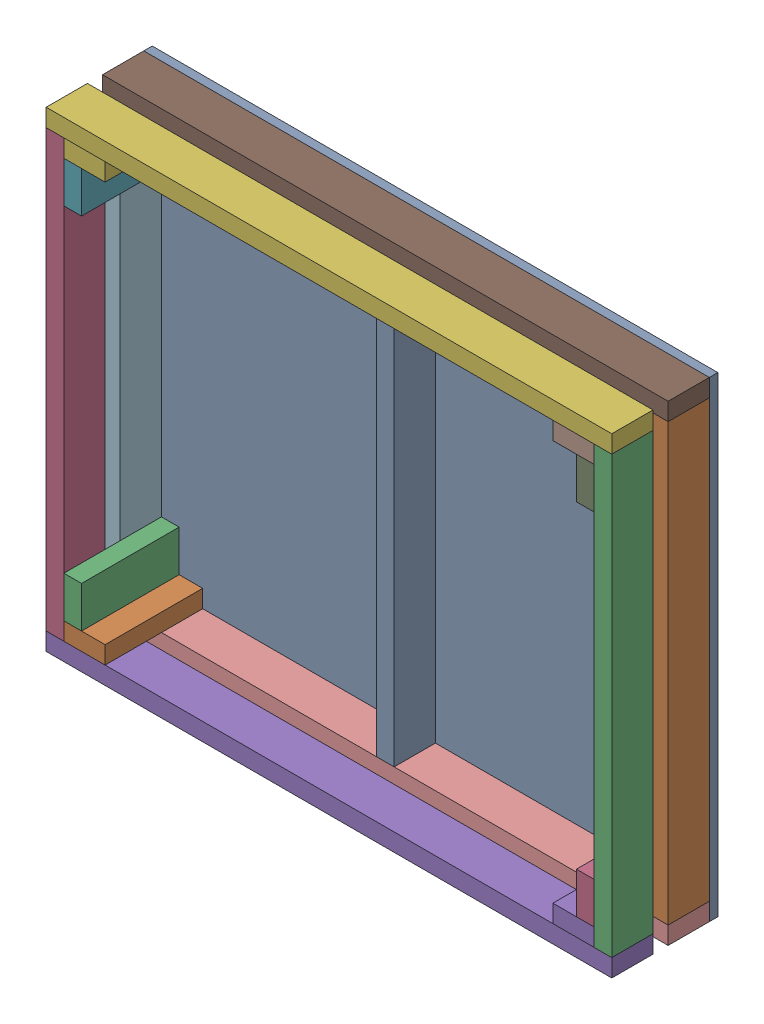
SolidWorks assembly TE-19103, configuration Default. Lengths in mm.
Overall size (1219.2 1016 228.6).
18 component instances, 4 part files, 61 mates.
Components (placement in the parent):
- TE-19103-01-1: TE-19103-01 [Default] at (153.7904 631.9704 926.4569) size (1219.2 1016 18.26)
- TE-19103-02-1: TE-19103-02 [Default] at (-77.2876 195.0062 1155.0569) x (-1 0 0) z (0 0 -1) size (88.9 38.1 210.34)
- TE-19103-02-2: TE-19103-02 [Default] at (-115.6981 316.4092 1155.0569) x (0 -1 0) z (0 0 -1) size (88.9 38.1 210.34)
- TE-19103-02-3: TE-19103-02 [Default] at (989.2019 316.4092 1155.0569) x (0 -1 0) z (0 0 -1) size (88.9 38.1 210.34)
- TE-19103-02-4: TE-19103-02 [Default] at (976.8124 195.0062 1155.0569) x (-1 0 0) z (0 0 -1) size (88.9 38.1 210.34)
- TE-19103-02-5: TE-19103-02 [Default] at (-148.2012 1141.5986 1155.0569) x (1 0 0) z (0 0 -1) size (88.9 38.1 210.34)
- TE-19103-02-6: TE-19103-02 [Default] at (-115.6981 1091.1092 1155.0569) x (0 -1 0) z (0 0 -1) size (88.9 38.1 210.34)
- TE-19103-02-7: TE-19103-02 [Default] at (976.8124 1096.7062 1155.0569) x (-1 0 0) z (0 0 -1) size (88.9 38.1 210.34)
- TE-19103-02-8: TE-19103-02 [Default] at (989.2019 1091.1092 1155.0569) x (0 -1 0) z (0 0 -1) size (88.9 38.1 210.34)
- TE-19103-03-1: TE-19103-03 [Default] at (-195.2944 160.3024 995.9796) x (0 -1 0) z (1 0 0) size (38.1 88.9 1219.2)
- TE-19103-03-2: TE-19103-03 [Default] at (1023.9056 1176.3024 995.9796) x (0 1 0) z (-1 0 0) size (38.1 88.9 1219.2)
- TE-19103-04-1: TE-19103-04 [Default] at (-157.1944 198.4024 1009.1746) x (1 0 0) z (0 1 0) size (38.1 88.9 939.8)
- TE-19103-04-2: TE-19103-04 [Default] at (433.3556 198.4024 1009.1746) x (1 0 0) z (0 1 0) size (38.1 88.9 939.8)
- TE-19103-04-3: TE-19103-04 [Default] at (1023.9056 1138.2024 969.1516) x (1 0 0) z (0 -1 0) size (38.1 88.9 939.8)
- TE-19103-04-4: TE-19103-04 [Default] at (985.8056 1138.2024 1130.6184) x (-1 0 0) z (0 -1 0) size (38.1 88.9 939.8)
- TE-19103-04-5: TE-19103-04 [Default] at (-157.1944 198.4024 1130.6184) x (1 0 0) z (0 1 0) size (38.1 88.9 939.8)
- TE-19103-03-3: TE-19103-03 [Default] at (1023.9056 160.3024 1103.7904) x (0 -1 0) z (-1 0 0) size (38.1 88.9 1219.2)
- TE-19103-03-4: TE-19103-03 [Default] at (1023.9056 1176.3024 1117.4233) x (0 1 0) z (-1 0 0) size (38.1 88.9 1219.2)
Mates (geometry in assembly coordinates):
- Coincident1: coincident: plane of TE-19103-01-1 through (153.7904 631.9704 944.7131) normal (0 0 1); plane of TE-19103-03-2 through (-195.2944 1138.2024 944.7131) normal (0 0 -1)
- Coincident2: coincident: plane of TE-19103-01-1 through (-195.2944 1176.3024 944.7131) normal (0 1 0); plane of TE-19103-03-2 through (-195.2944 1176.3024 944.7131) normal (0 1 0)
- Coincident3: coincident: plane of TE-19103-01-1 through (1023.9056 1176.3024 944.7131) normal (1 0 0); plane of TE-19103-03-2 through (1023.9056 1176.3024 995.9796) normal (1 0 0)
- Coincident4: coincident: plane of TE-19103-01-1 through (153.7904 631.9704 944.7131) normal (0 0 1); plane of TE-19103-03-1 through (1023.9056 198.4024 944.7131) normal (0 0 -1)
- Coincident6: coincident: plane of assembly; plane of assembly; plane of TE-19103-03-1 through (1023.9056 160.3024 995.9796) normal (1 0 0); plane of TE-19103-03-2 through (1023.9056 1176.3024 995.9796) normal (1 0 0)
- Coincident7: coincident: plane of TE-19103-01-1 through (-195.2944 160.3024 944.7131) normal (0 -1 0); plane of TE-19103-03-1 through (1023.9056 160.3024 944.7131) normal (0 -1 0)
- Coincident8: coincident: plane of TE-19103-01-1 through (153.7904 631.9704 944.7131) normal (0 0 1); plane of TE-19103-04-3 through (985.8056 198.4024 944.7131) normal (0 0 -1)
- Coincident9: coincident: plane of assembly; plane of assembly; plane of TE-19103-03-1 through (1023.9056 198.4024 944.7131) normal (0 1 0); plane of TE-19103-04-3 through (1023.9056 198.4024 969.1516) normal (0 -1 0)
- Coincident10: coincident: plane of assembly; plane of assembly; plane of TE-19103-03-1 through (1023.9056 160.3024 995.9796) normal (1 0 0); plane of TE-19103-04-3 through (1023.9056 198.4024 1033.6131) normal (1 0 0)
- Coincident11: coincident: plane of assembly; plane of assembly; plane of TE-19103-03-2 through (-195.2944 1138.2024 944.7131) normal (0 -1 0); plane of TE-19103-04-1 through (-157.1944 1138.2024 1009.1746) normal (0 1 0)
- Coincident12: coincident: plane of TE-19103-01-1 through (153.7904 631.9704 944.7131) normal (0 0 1); plane of TE-19103-04-1 through (-195.2944 1138.2024 944.7131) normal (0 0 -1)
- Coincident13: coincident: plane of assembly; plane of assembly; plane of TE-19103-03-2 through (-195.2944 1176.3024 995.9796) normal (-1 0 0); plane of TE-19103-04-1 through (-195.2944 1138.2024 944.7131) normal (-1 0 0)
- Coincident14: coincident: plane of TE-19103-02-5 through (-157.1944 1100.1024 944.7131) normal (0 -1 0); unknown of ?
- Coincident15: coincident: plane of assembly; plane of assembly; plane of TE-19103-02-5 through (-148.2012 1141.5986 944.7131) normal (0 0 -1); plane of TE-19103-02-6 through (-115.6981 1091.1092 944.7131) normal (0 0 -1)
- Coincident16: coincident: plane of TE-19103-02-5 through (-157.1944 1100.1024 944.7131) normal (-1 0 0); unknown of ?
- Coincident17: coincident: plane of TE-19103-01-1 through (153.7904 631.9704 944.7131) normal (0 0 1); plane of TE-19103-02-6 through (-115.6981 1091.1092 944.7131) normal (0 0 -1)
- Coincident18: coincident: plane of assembly; plane of assembly; plane of TE-19103-02-5 through (-157.1944 1138.2024 944.7131) normal (0 1 0); plane of TE-19103-03-2 through (-195.2944 1138.2024 944.7131) normal (0 -1 0)
- Coincident19: coincident: unknown of ?; plane of TE-19103-04-1 through (-157.1944 1138.2024 944.7131) normal (1 0 0)
- Symmetric1: symmetric: plane of assembly; plane of assembly; plane of TE-19103-04-2 through (433.3556 1138.2024 944.7131) normal (1 0 0); plane of TE-19103-04-2 through (395.2556 1138.2024 944.7131) normal (-1 0 0); plane of assembly
- Coincident20: coincident: plane of TE-19103-01-1 through (153.7904 631.9704 944.7131) normal (0 0 1); plane of TE-19103-04-2 through (395.2556 1138.2024 944.7131) normal (0 0 -1)
- Coincident21: coincident: plane of assembly; plane of assembly; plane of TE-19103-03-1 through (1023.9056 198.4024 944.7131) normal (0 1 0); plane of TE-19103-04-2 through (433.3556 198.4024 1009.1746) normal (0 -1 0)
- Coincident22: coincident: plane of TE-19103-02-7 through (985.8056 1100.1024 944.7131) normal (0 -1 0); plane of ? through (985.8056 1100.1024 944.7131) normal (0 1 0)
- Coincident23: coincident: plane of TE-19103-02-7 through (896.9056 1138.2024 944.7131) normal (-1 0 0); plane of ? through (896.9056 1100.1024 944.7131) normal (-1 0 0)
- Coincident24: coincident: plane of assembly; plane of assembly; plane of TE-19103-02-7 through (976.8124 1096.7062 944.7131) normal (0 0 -1); plane of TE-19103-02-8 through (989.2019 1091.1092 944.7131) normal (0 0 -1)
- Coincident25: coincident: plane of TE-19103-01-1 through (153.7904 631.9704 944.7131) normal (0 0 1); plane of TE-19103-02-8 through (989.2019 1091.1092 944.7131) normal (0 0 -1)
- Coincident26: coincident: plane of assembly; plane of assembly; plane of TE-19103-02-7 through (985.8056 1138.2024 944.7131) normal (1 0 0); plane of TE-19103-04-3 through (985.8056 198.4024 1033.6131) normal (-1 0 0)
- Coincident27: coincident: plane of assembly; plane of assembly; plane of TE-19103-02-7 through (985.8056 1138.2024 944.7131) normal (0 1 0); plane of TE-19103-03-2 through (-195.2944 1138.2024 944.7131) normal (0 -1 0)
- Coincident28: coincident: plane of TE-19103-02-1 through (-68.2944 236.5024 944.7131) normal (0 1 0); unknown of ?
- Coincident29: coincident: plane of TE-19103-02-1 through (-68.2944 236.5024 944.7131) normal (1 0 0); unknown of ?
- Coincident30: coincident: plane of assembly; plane of assembly; plane of TE-19103-02-1 through (-77.2876 195.0062 944.7131) normal (0 0 -1); plane of TE-19103-02-2 through (-115.6981 316.4092 944.7131) normal (0 0 -1)
- Coincident31: coincident: plane of TE-19103-01-1 through (153.7904 631.9704 944.7131) normal (0 0 1); plane of TE-19103-02-2 through (-115.6981 316.4092 944.7131) normal (0 0 -1)
- Coincident32: coincident: plane of assembly; plane of assembly; plane of TE-19103-02-1 through (-157.1944 236.5024 944.7131) normal (-1 0 0); plane of TE-19103-04-1 through (-157.1944 1138.2024 944.7131) normal (1 0 0)
- Coincident33: coincident: plane of assembly; plane of assembly; plane of TE-19103-02-1 through (-68.2944 198.4024 944.7131) normal (0 -1 0); plane of TE-19103-03-1 through (1023.9056 198.4024 944.7131) normal (0 1 0)
- Coincident34: coincident: unknown of ?; plane of TE-19103-02-4 through (985.8056 236.5024 944.7131) normal (0 1 0)
- Coincident35: coincident: unknown of ?; plane of TE-19103-02-4 through (896.9056 236.5024 944.7131) normal (-1 0 0)
- Coincident36: coincident: plane of assembly; plane of assembly; plane of TE-19103-02-3 through (989.2019 316.4092 944.7131) normal (0 0 -1); plane of TE-19103-02-4 through (976.8124 195.0062 944.7131) normal (0 0 -1)
- Coincident37: coincident: plane of TE-19103-01-1 through (153.7904 631.9704 944.7131) normal (0 0 1); plane of TE-19103-02-3 through (989.2019 316.4092 944.7131) normal (0 0 -1)
- Coincident38: coincident: plane of assembly; plane of assembly; plane of TE-19103-02-4 through (985.8056 236.5024 944.7131) normal (1 0 0); plane of TE-19103-04-3 through (985.8056 198.4024 1033.6131) normal (-1 0 0)
- Coincident39: coincident: plane of assembly; plane of assembly; plane of TE-19103-02-4 through (985.8056 198.4024 944.7131) normal (0 -1 0); plane of TE-19103-03-1 through (1023.9056 198.4024 944.7131) normal (0 1 0)
- Coincident43: coincident: unknown of ?; plane of ? through (-157.1944 435.2774 1341.1994) normal (1 0 0)
- Coincident44: coincident: plane of assembly; plane of assembly; plane of TE-19103-02-1 through (-77.2876 195.0062 1155.0569) normal (0 0 1); plane of TE-19103-04-5 through (-195.2944 1138.2024 1155.0569) normal (0 0 1)
- Coincident45: coincident: plane of assembly; plane of assembly; plane of TE-19103-02-1 through (-68.2944 198.4024 944.7131) normal (0 -1 0); plane of TE-19103-04-5 through (-157.1944 198.4024 1130.6184) normal (0 -1 0)
- Coincident49: coincident: plane of assembly; plane of assembly; plane of TE-19103-02-4 through (976.8124 195.0062 1155.0569) normal (0 0 1); plane of TE-19103-04-4 through (1023.9056 198.4024 1155.0569) normal (0 0 1)
- Coincident50: coincident: plane of assembly; plane of assembly; plane of TE-19103-02-7 through (985.8056 1138.2024 944.7131) normal (0 1 0); plane of TE-19103-04-4 through (985.8056 1138.2024 1130.6184) normal (0 1 0)
- Coincident51: coincident: unknown of ?; plane of ? through (985.8056 901.3274 1341.1994) normal (-1 0 0)
- Coincident52: coincident: plane of assembly; plane of assembly; plane of TE-19103-02-5 through (-157.1944 1100.1024 944.7131) normal (0 -1 0); plane of TE-19103-02-6 through (-157.1944 1100.1024 944.7131) normal (0 1 0)
- Coincident53: coincident: plane of assembly; plane of assembly; plane of TE-19103-02-6 through (-157.1944 1100.1024 944.7131) normal (-1 0 0); plane of TE-19103-04-1 through (-157.1944 1138.2024 944.7131) normal (1 0 0)
- Coincident54: coincident: plane of assembly; plane of assembly; plane of TE-19103-02-7 through (985.8056 1100.1024 944.7131) normal (0 -1 0); plane of TE-19103-02-8 through (947.7056 1100.1024 944.7131) normal (0 1 0)
- Coincident55: coincident: plane of assembly; plane of assembly; plane of TE-19103-02-8 through (985.8056 1100.1024 944.7131) normal (1 0 0); plane of TE-19103-04-3 through (985.8056 198.4024 1033.6131) normal (-1 0 0)
- Coincident56: coincident: plane of assembly; plane of assembly; plane of TE-19103-02-2 through (-157.1944 325.4024 944.7131) normal (-1 0 0); plane of TE-19103-04-1 through (-157.1944 1138.2024 944.7131) normal (1 0 0)
- Coincident57: coincident: plane of assembly; plane of assembly; plane of TE-19103-02-1 through (-68.2944 236.5024 944.7131) normal (0 1 0); plane of TE-19103-02-2 through (-157.1944 236.5024 944.7131) normal (0 -1 0)
- Coincident58: coincident: plane of assembly; plane of assembly; plane of TE-19103-02-3 through (985.8056 325.4024 944.7131) normal (1 0 0); plane of TE-19103-04-4 through (985.8056 198.4024 1066.1569) normal (-1 0 0)
- Coincident59: coincident: plane of assembly; plane of assembly; plane of TE-19103-02-3 through (947.7056 236.5024 944.7131) normal (0 -1 0); plane of TE-19103-02-4 through (985.8056 236.5024 944.7131) normal (0 1 0)
- Coincident60: coincident: plane of assembly; plane of assembly; plane of TE-19103-02-3 through (985.8056 325.4024 944.7131) normal (1 0 0); plane of TE-19103-04-3 through (985.8056 198.4024 1033.6131) normal (-1 0 0)
- Coincident61: coincident: plane of assembly; plane of assembly; plane of TE-19103-02-2 through (-157.1944 325.4024 944.7131) normal (-1 0 0); plane of TE-19103-04-5 through (-157.1944 1138.2024 1066.1569) normal (1 0 0)
- Coincident62: coincident: plane of assembly; plane of assembly; plane of TE-19103-02-1 through (-68.2944 198.4024 944.7131) normal (0 -1 0); plane of TE-19103-03-3 through (-195.2944 198.4024 1155.0569) normal (0 1 0)
- Coincident63: coincident: plane of assembly; plane of assembly; plane of TE-19103-04-5 through (-195.2944 1138.2024 1066.1569) normal (-1 0 0); plane of TE-19103-03-3 through (-195.2944 160.3024 1103.7904) normal (-1 0 0)
- Coincident64: coincident: plane of assembly; plane of assembly; plane of TE-19103-02-1 through (-77.2876 195.0062 1155.0569) normal (0 0 1); plane of TE-19103-03-3 through (-195.2944 198.4024 1155.0569) normal (0 0 1)
- Coincident65: coincident: plane of assembly; plane of assembly; plane of TE-19103-02-5 through (-157.1944 1138.2024 944.7131) normal (0 1 0); plane of TE-19103-03-4 through (-195.2944 1138.2024 1066.1569) normal (0 -1 0)
- Coincident66: coincident: plane of assembly; plane of assembly; plane of TE-19103-04-5 through (-195.2944 1138.2024 1066.1569) normal (-1 0 0); plane of TE-19103-03-4 through (-195.2944 1176.3024 1117.4233) normal (-1 0 0)
- Coincident67: coincident: plane of assembly; plane of assembly; plane of TE-19103-02-6 through (-115.6981 1091.1092 1155.0569) normal (0 0 1); plane of TE-19103-03-4 through (-195.2944 1138.2024 1155.0569) normal (0 0 1)
